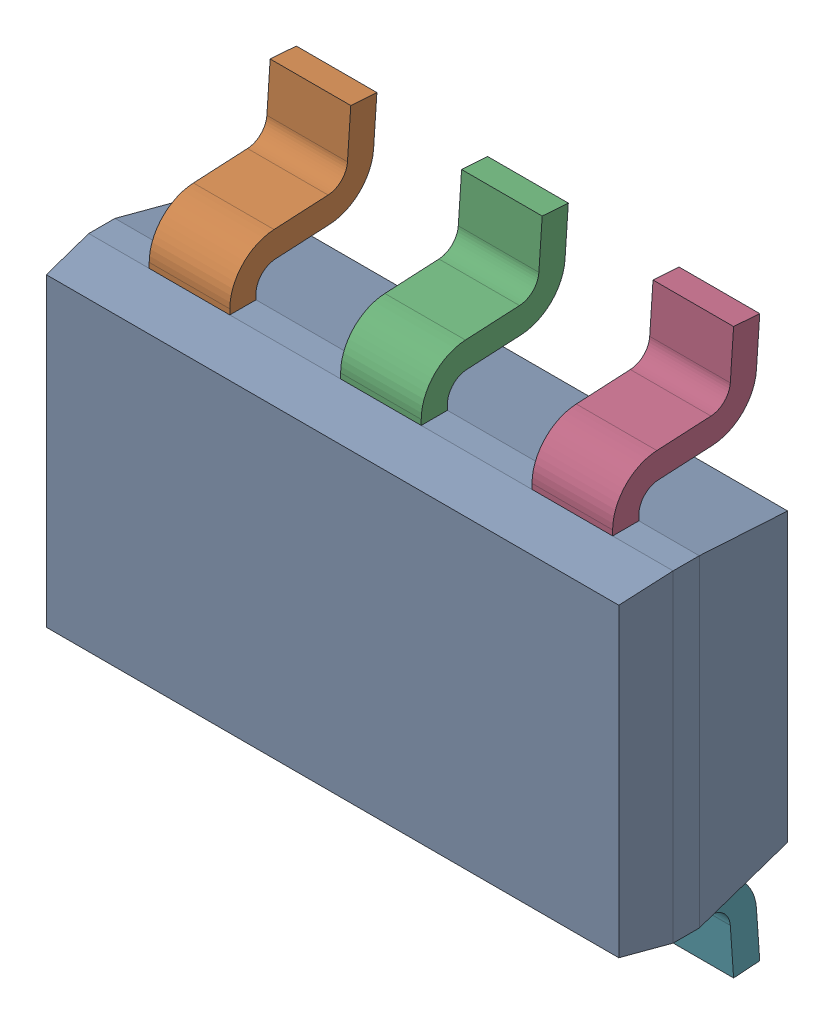
SolidWorks assembly U13, configuration ﾃﾞﾌｫﾙﾄ. Lengths in mm.
Overall size (2.9 2.8 0.97).
8 component instances, 2 part files, 0 mates.
Components (placement in the parent):
- DDC0006A-1: DDC0006A [ﾃﾞﾌｫﾙﾄ] at (39.37 22.5425 0) x (0 1 0) z (0 0 1) size (2.8 2.9 0.97)
  - BODY-SOT-1: BODY-SOT [ﾃﾞﾌｫﾙﾄ] at (0 0 0.73) x (0 1 0) z (1 0 0) size (2.9 0.87 1.6)
  - LEAD-SOT-1: LEAD-SOT [ﾃﾞﾌｫﾙﾄ] at (0.9409 0.95 0.25) x (0 1 0) z (1 0 0) size (0.4 0.73 0.6)
  - LEAD-SOT-2: LEAD-SOT [ﾃﾞﾌｫﾙﾄ] at (0.9409 0 0.25) x (0 1 0) z (1 0 0) size (0.4 0.73 0.6)
  - LEAD-SOT-3: LEAD-SOT [ﾃﾞﾌｫﾙﾄ] at (0.9409 -0.95 0.25) x (0 1 0) z (1 0 0) size (0.4 0.73 0.6)
  - LEAD-SOT-4: LEAD-SOT [ﾃﾞﾌｫﾙﾄ] at (-0.9409 0.95 0.25) x (0 -1 0) z (-1 0 0) size (0.4 0.73 0.6)
  - LEAD-SOT-5: LEAD-SOT [ﾃﾞﾌｫﾙﾄ] at (-0.9409 0 0.25) x (0 -1 0) z (-1 0 0) size (0.4 0.73 0.6)
  - LEAD-SOT-6: LEAD-SOT [ﾃﾞﾌｫﾙﾄ] at (-0.9409 -0.95 0.25) x (0 -1 0) z (-1 0 0) size (0.4 0.73 0.6)
